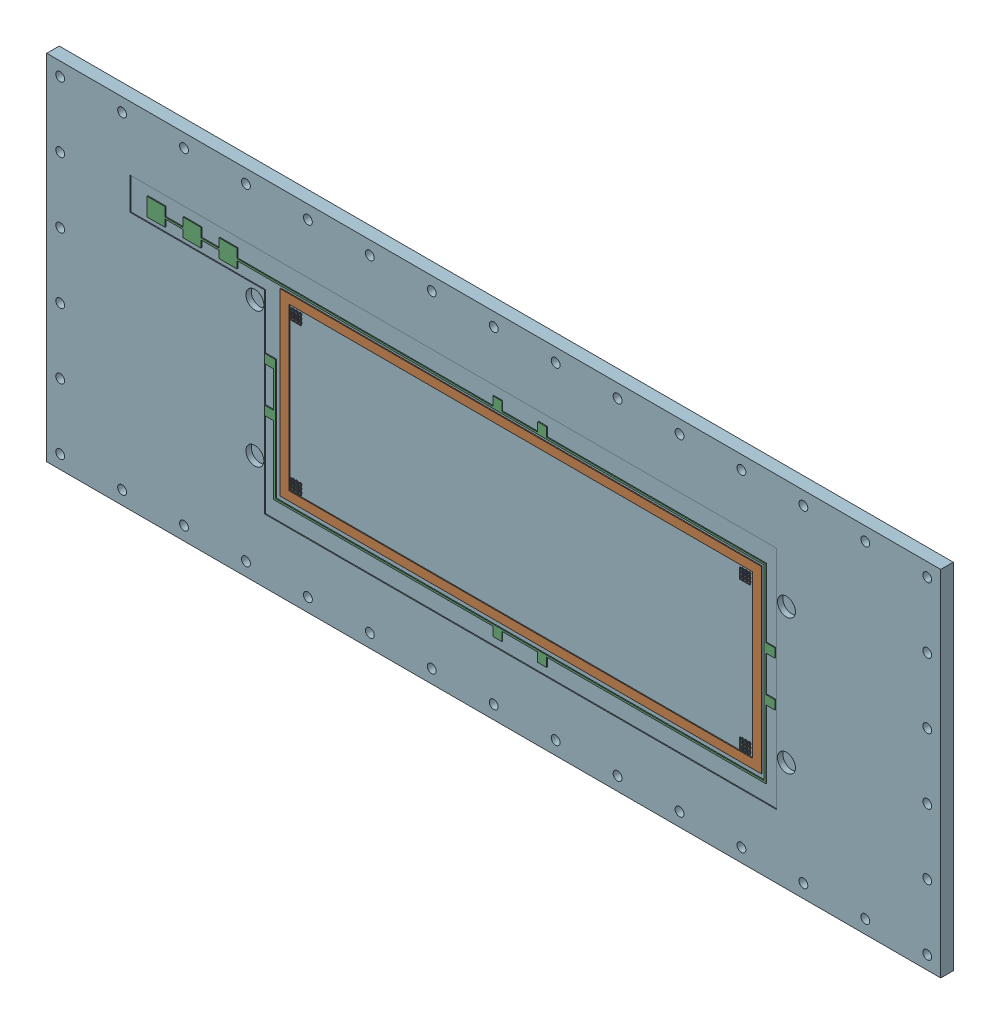
SolidWorks assembly MCPP, configuration Default. Lengths in mm.
Overall size (497.8 197 7.5).
3 component instances, 3 part files, 0 mates.
Components (placement in the parent):
- _MCPP-1: _MCPP [Default] at (0.8116 8.7085 3.35) size (497.8 197 7.3)
- _MCPP_1-1: _MCPP_1 [Default] at (0.8116 8.7085 3.35) x (1 0 0) z (0 0 -1) size (268 100 0.5)
- _MCPP_2-1: _MCPP_2 [Default] at (0.8116 8.7085 3.35) size (349.5 116 0.5)
